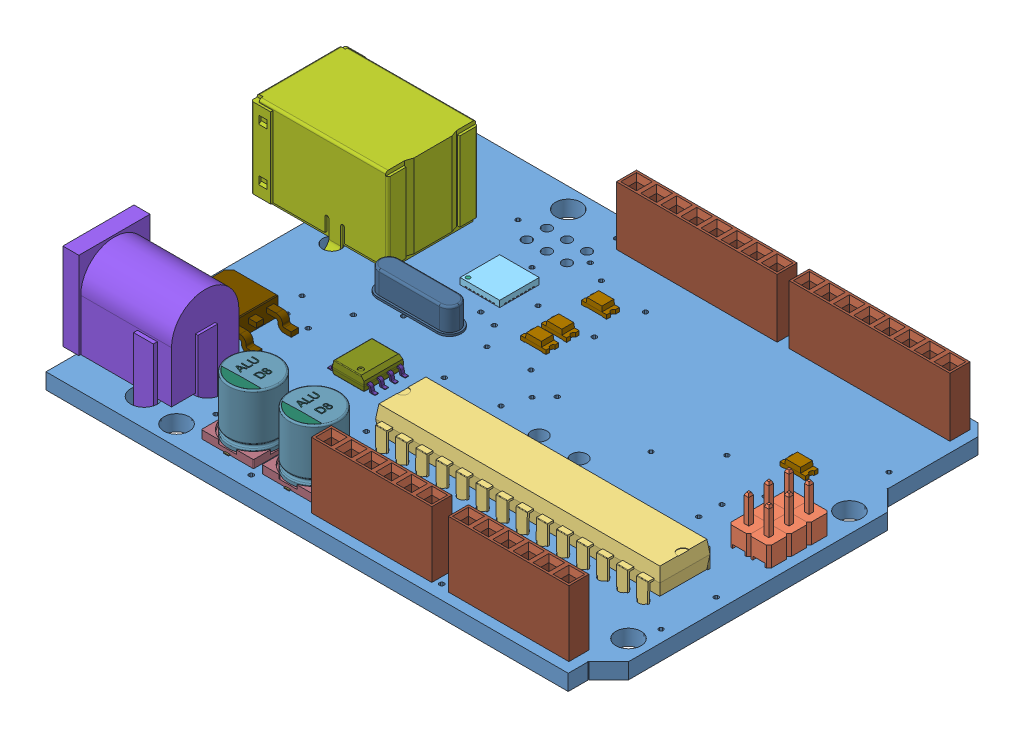
SolidWorks assembly Final, configuration Predeterminado. Lengths in mm.
Overall size (74.75 15.43 53.34).
32 component instances, 18 part files, 18 mates.
Components (placement in the parent):
- PCB_Final-1: PCB_Final [Default] at origin size (68.58 2 53.34)
- Header Vertical 2.54mm Pitch2-1: Header Vertical 2.54mm Pitch2 [Header 6 Way] at (62.2731 2 -29.1415) size (5.08 8.88 7.62)
- IC DIP 28-1: IC DIP 28 [Default] at (51.4233 4.3498 -16.4837) x (0 0.005002 0.999987) z (-1 0 0) size (7.87 6.22 35.94)
- User Library-QFN32 (FTDI)-1: User Library-QFN32 (FTDI) [Default] at (19.2089 2.05 -38.1588) x (-1 0 0) z (0 1 0) size (5 5 0.85)
  - User Library-QFN32 (FTDI)_Anschl_X_FCsse_1-1: User Library-QFN32 (FTDI)_Anschl_X_FCsse_1 [Default] x (0 -1 0) z (0 0 1) size (5 5 0.2)
  - User Library-QFN32 (FTDI)_K_X_F6rper_1-1: User Library-QFN32 (FTDI)_K_X_F6rper_1 [Default] at origin size (5 5 0.8)
  - User Library-QFN32 (FTDI)_Beschriftung_1-1: User Library-QFN32 (FTDI)_Beschriftung_1 [Default] at origin size (0.51 0.51 0.05)
- User Library-67068-0000-molex-1: User Library-67068-0000-molex [Default] at (-6.1546 2 -38.0545) x (0.002421 0 0.999997) z (-0.999997 0 0.002421) size (14.9 15.43 17)
- User Library-dc range - dc connector[4840_2201]-1: User Library-dc range - dc connector[4840_2201] [Default] at (11.794 2 -12.8354) x (0 0 1) z (-1 0 0) size (9.51 14.5 13.83)
- LED 1206-2: LED 1206 [Default] at (28.1068 2 -36.9237) x (0 0 -1) z (1 0 0) size (1.6 1.1 3.2)
- LED 1206-3: LED 1206 [Default] at (28.142 2 -34.2868) x (0 0 -1) z (1 0 0) size (1.6 1.1 3.2)
- LED 1206-4: LED 1206 [Default] at (58.3346 2 -36.8813) x (0 0 -1) z (1 0 0) size (1.6 1.1 3.2)
- LED 1206-5: LED 1206 [Default] at (28.1068 2 -41.994) x (0 0 -1) z (1 0 0) size (1.6 1.1 3.2)
- XTAL Small-1: XTAL Small [Default] at (14.2222 2 -30.4346) x (1 0 0) z (0 1 0) size (10.67 3.05 5.63)
- Stackable Female Pin Header-1: Stackable Female Pin Header [6 Way] at (50.8347 2 -2.5872) size (15.24 8.3 2.54)
- Stackable Female Pin Header-2: Stackable Female Pin Header [Default] at (45.7158 1.1368 -50.806) size (20.32 8.3 2.54)
- Stackable Female Pin Header-3: Stackable Female Pin Header [Default] at (23.9415 1.1201 -50.7298) size (20.32 8.3 2.54)
- Stackable Female Pin Header-4: Stackable Female Pin Header [6 Way] at (33.5006 2 -2.5872) size (15.24 8.3 2.54)
- User Library-ALU-D8-1: User Library-ALU-D8 [Default] at (20.4464 1.8 -5.7935) x (0 0 -1) z (0 1 0) size (7 6.6 7.71)
  - User Library-ALU-D8_Pins_1-1: User Library-ALU-D8_Pins_1 [Default] at origin size (7 0.65 0.4)
  - User Library-ALU-D8_Fuss_1-1: User Library-ALU-D8_Fuss_1 [Default] at origin size (6.6 6.6 1)
  - User Library-ALU-D8_K_X_F6rper_1-1: User Library-ALU-D8_K_X_F6rper_1 [Default] at origin size (6.3 6.3 7)
  - User Library-ALU-D8_Beschriftung_1-1: User Library-ALU-D8_Beschriftung_1 [Default] at origin size (4.36 4.98 0.11)
- User Library-ALU-D8-2: User Library-ALU-D8 [Default] at (28.1214 1.8 -5.7935) x (0 0 -1) z (0 1 0) size (7 6.6 7.71)
  - User Library-ALU-D8_Pins_1-1: User Library-ALU-D8_Pins_1 [Default] at origin size (7 0.65 0.4)
  - User Library-ALU-D8_Fuss_1-1: User Library-ALU-D8_Fuss_1 [Default] at origin size (6.6 6.6 1)
  - User Library-ALU-D8_K_X_F6rper_1-1: User Library-ALU-D8_K_X_F6rper_1 [Default] at origin size (6.3 6.3 7)
  - User Library-ALU-D8_Beschriftung_1-1: User Library-ALU-D8_Beschriftung_1 [Default] at origin size (4.36 4.98 0.11)
- User Library-SOIC-8-1: User Library-SOIC-8 [Default] at (20.4108 1.85 -20.3024) x (0 0 -1) z (1 0 0) size (5 1.75 6.01)
  - User Library-SOIC-8_SOIC-8_Body_1-1: User Library-SOIC-8_SOIC-8_Body_1 [Default] at origin size (5 1.6 4)
  - User Library-SOIC-8_SOIC-8_Pins_1-1: User Library-SOIC-8_SOIC-8_Pins_1 [Default] at origin size (4.23 0.99 6.01)
- SO 369A-1: SO 369A [Standard] at (5.5398 2 -17.4191) x (0 0 -1) z (0 1 0) size (6.6 10.1 2.4)
Mates (geometry in assembly coordinates):
- Coincidente1: coincident anti-aligned: plane of PCB_Final-1 through (-33.5843 2 -26.6884) normal (0 1 0); plane of Header Vertical 2.54mm Pitch2-1 through (63.8431 2 -27.8715) normal (0 -1 0)
- Coincidente2: coincident anti-aligned: plane of PCB_Final-1 through (-33.5843 2 -26.6884) normal (0 1 0); plane of User Library-QFN32 (FTDI)-1/User Library-QFN32 (FTDI)_Anschl_X_FCsse_1-1 through (19.2089 2 -38.1588) normal (0 -1 0)
- Coincidente3: coincident anti-aligned: plane of PCB_Final-1 through (-33.5843 2 -26.6884) normal (0 1 0); plane of User Library-67068-0000-molex-1 through (10.8308 2 -44.0956) normal (0 -1 0)
- Coincidente4: coincident anti-aligned: plane of PCB_Final-1 through (-33.5843 2 -26.6884) normal (0 1 0); plane of User Library-dc range - dc connector[4840_2201]-1 through (-1.706 2 -12.8354) normal (0 -1 0)
- Paralelo1: parallel: line of PCB_Final-1 through (66.04 2 0) axis (-1 0 0); plane of User Library-dc range - dc connector[4840_2201]-1 through (0.3218 7.6431 -4.0756) normal (0 0 1)
- Coincidente7: coincident: plane of PCB_Final-1 through (-33.5843 2 -26.6884) normal (0 1 0); plane of LED 1206-2 through (29.7068 2 -37.7237) normal (0 -1 0)
- Paralelo2: parallel: line of PCB_Final-1 through (0 2 0) axis (0 0 -1); line of LED 1206-2 through (29.7068 2.5 -36.5883) axis (0 0 1)
- Coincidente10: coincident anti-aligned: plane of PCB_Final-1 through (-33.5843 2 -26.6884) normal (0 1 0); plane of XTAL Small-1 through (11.6822 2 -31.7046) normal (0 -1 0)
- Coincidente11: coincident anti-aligned: plane of PCB_Final-1 through (-33.5843 2 -26.6884) normal (0 1 0); plane of Stackable Female Pin Header-1 through (49.5647 2 -1.3172) normal (0 -1 0)
- Coincidente12: coincident aligned: plane of Stackable Female Pin Header-1 through (52.1047 10.3 -1.3172) normal (0 0 1); plane of Stackable Female Pin Header-4 through (34.7706 10.3 -1.3172) normal (0 0 1)
- Coincidente14: coincident anti-aligned: plane of PCB_Final-1 through (-33.5843 2 -26.6884) normal (0 1 0); plane of Stackable Female Pin Header-4 through (32.2306 2 -1.3172) normal (0 -1 0)
- Coincidente19: coincident anti-aligned: plane of PCB_Final-1 through (-33.5843 2 -26.6884) normal (0 1 0); plane of User Library-ALU-D8-1/User Library-ALU-D8_Fuss_1-1 through (20.4464 2 -5.5067) normal (0 -1 0)
- Paralelo4: parallel anti-aligned: line of PCB_Final-1 through (66.04 2 0) axis (-1 0 0); line of User Library-ALU-D8-1/User Library-ALU-D8_Fuss_1-1 through (20.7964 2 -2.4935) axis (1 0 0)
- Coincidente21: coincident anti-aligned: plane of PCB_Final-1 through (-33.5843 2 -26.6884) normal (0 1 0); plane of User Library-SOIC-8-1/User Library-SOIC-8_SOIC-8_Body_1-1 through (20.4108 2 -20.3024) normal (0 -1 0)
- Paralelo5: parallel aligned: line of PCB_Final-1 through (66.04 2 0) axis (-1 0 0); line of User Library-SOIC-8-1/User Library-SOIC-8_SOIC-8_Body_1-1 through (22.346 2.0878 -17.8671) axis (-1 0 0)
- Paralelo6: parallel aligned: line of PCB_Final-1 through (0 2 0) axis (0 0 -1); line of User Library-QFN32 (FTDI)-1/User Library-QFN32 (FTDI)_K_X_F6rper_1-1 through (16.7089 2.85 -35.6588) axis (0 0 -1)
- Coincidente22: coincident anti-aligned: plane of PCB_Final-1 through (-33.5843 2 -26.6884) normal (0 1 0); plane of SO 369A-1 through (2.4398 2 -14.1191) normal (0 -1 0)
- Paralelo7: parallel aligned: line of PCB_Final-1 through (0 2 0) axis (0 0 -1); line of SO 369A-1 through (1.9398 2.6 -15.7191) axis (0 0 -1)
